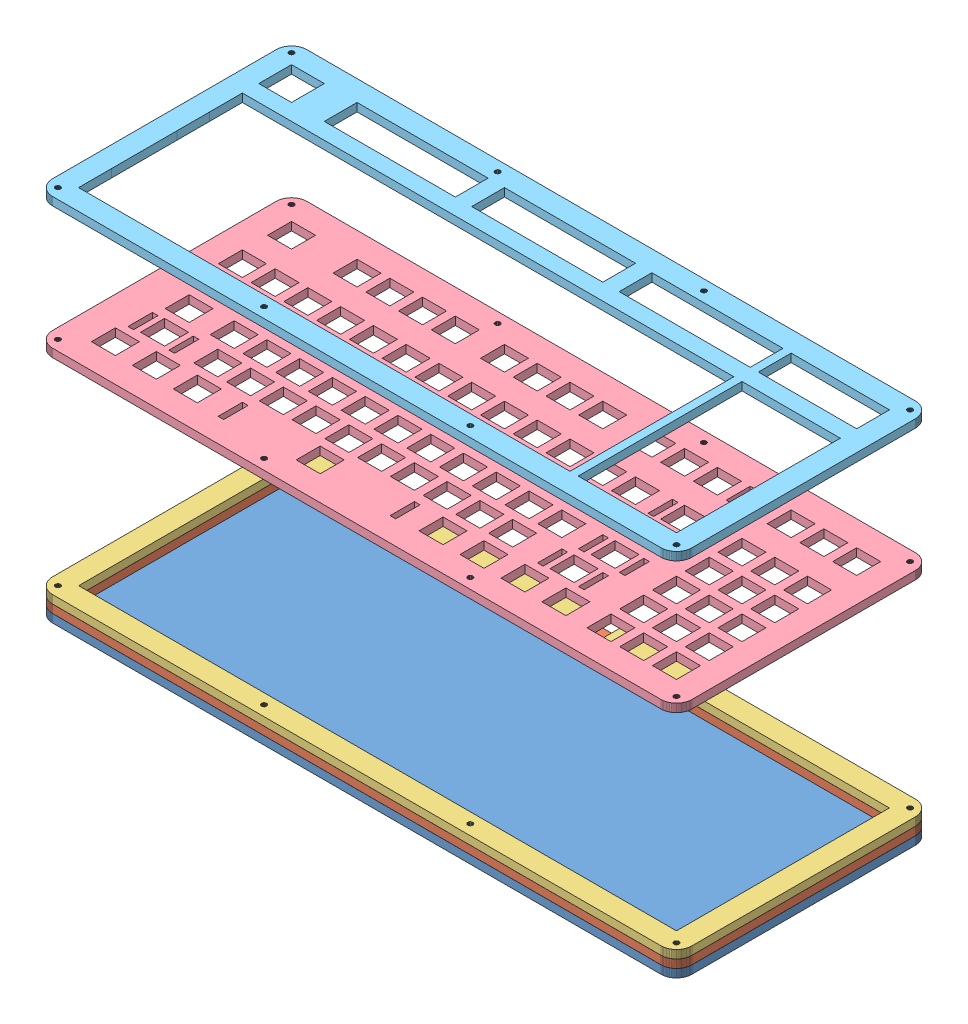
SolidWorks assembly Assem1, configuration Default. Lengths in mm.
Overall size (371.71 214.79 147.88).
5 component instances, 5 part files, 12 mates.
Components (placement in the parent):
- BottomLayer-1: BottomLayer [Default] at (-39.9401 211.4104 342.0609) size (371.71 4.76 147.88)
- ClosedLayer-1: ClosedLayer [Default] at (-39.9401 216.1989 342.0609) size (371.71 4.76 147.88)
- OpenLayer-1: OpenLayer [Default] at (-39.9401 220.9815 342.0609) size (371.71 4.76 147.88)
- SwitchLayer-1: SwitchLayer [Default] at (-39.9401 345.0381 342.0609) size (371.71 4.76 147.88)
- TopLayer-2: TopLayer [Default] at (-39.9401 421.4401 342.0609) size (371.71 4.76 147.88)
Mates (geometry in assembly coordinates):
- Coincident17: coincident: plane of BottomLayer-1 through (322.8669 216.1729 341.97) normal (0 0 1); plane of ClosedLayer-1 through (322.8669 220.9354 341.97) normal (0 0 1)
- Coincident18: coincident: plane of BottomLayer-1 through (322.8669 216.1729 341.97) normal (0 0 1); plane of TopLayer-2 through (322.8669 235.2229 341.97) normal (0 0 1)
- Coincident19: coincident: plane of BottomLayer-1 through (322.8669 216.1729 341.97) normal (0 0 1); plane of SwitchLayer-1 through (322.8669 230.4604 341.97) normal (0 0 1)
- Coincident20: coincident: plane of BottomLayer-1 through (322.8669 216.1729 341.97) normal (0 0 1); plane of OpenLayer-1 through (322.8669 225.6979 341.97) normal (0 0 1)
- Coincident21: coincident: plane of TopLayer-2 through (331.8669 235.2229 203.0939) normal (1 0 0); plane of SwitchLayer-1 through (331.8669 230.4604 203.0939) normal (1 0 0)
- Coincident22: coincident: plane of TopLayer-2 through (331.8669 235.2229 203.0939) normal (1 0 0); plane of OpenLayer-1 through (331.8669 225.6979 203.0939) normal (1 0 0)
- Coincident23: coincident: plane of TopLayer-2 through (331.8669 235.2229 203.0939) normal (1 0 0); plane of ClosedLayer-1 through (331.8669 220.9354 203.0939) normal (1 0 0)
- Coincident24: coincident: plane of TopLayer-2 through (331.8669 235.2229 203.0939) normal (1 0 0); plane of BottomLayer-1 through (331.8669 216.1729 203.0939) normal (1 0 0)
- Coincident25: coincident: plane of BottomLayer-1 through (-39.9401 216.1729 342.0609) normal (0 1 0); plane of ClosedLayer-1 through (-39.9401 216.1729 342.0609) normal (0 -1 0)
- Coincident26: coincident: plane of ClosedLayer-1 through (-39.9401 220.9354 342.0609) normal (0 1 0); plane of OpenLayer-1 through (-39.9401 220.9354 342.0609) normal (0 -1 0)
- Coincident27: coincident: plane of OpenLayer-1 through (-39.9401 225.6979 342.0609) normal (0 1 0); plane of SwitchLayer-1 through (-39.9401 225.6979 342.0609) normal (0 -1 0)
- Coincident28: coincident: plane of SwitchLayer-1 through (-39.9401 230.4604 342.0609) normal (0 1 0); plane of TopLayer-2 through (-39.9401 230.4604 342.0609) normal (0 -1 0)
